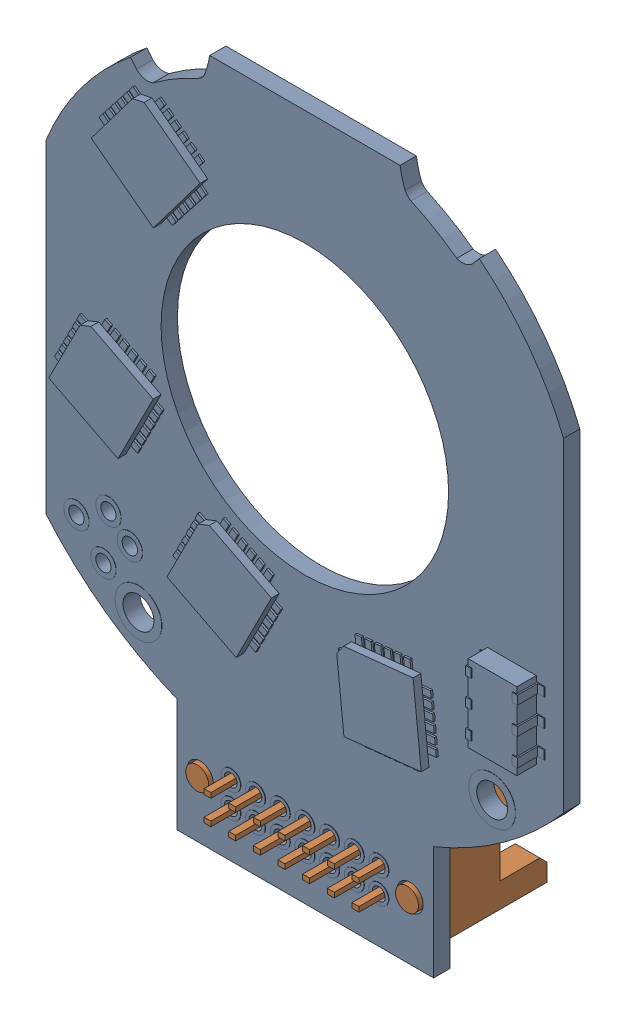
SolidWorks assembly CUI_DEVICES_Transmitter-board with connector(standard connector), configuration Default. Lengths in mm.
Overall size (26.63 35.37 7.65).
2 component instances, 2 part files, 0 mates.
Components (placement in the parent):
- CUI_DEVICES_Transmitter-board(AMT203-303)-1: CUI_DEVICES_Transmitter-board(AMT203-303) [Default] at origin size (26.63 35.37 1.96)
- CUI_DEVICES_TFM-107-01-X-D-A-1: CUI_DEVICES_TFM-107-01-X-D-A [Default] at (25.2099 -1.9489 -0.84) x (1 0 0) z (0 1 0) size (12.06 7.65 5.72)
